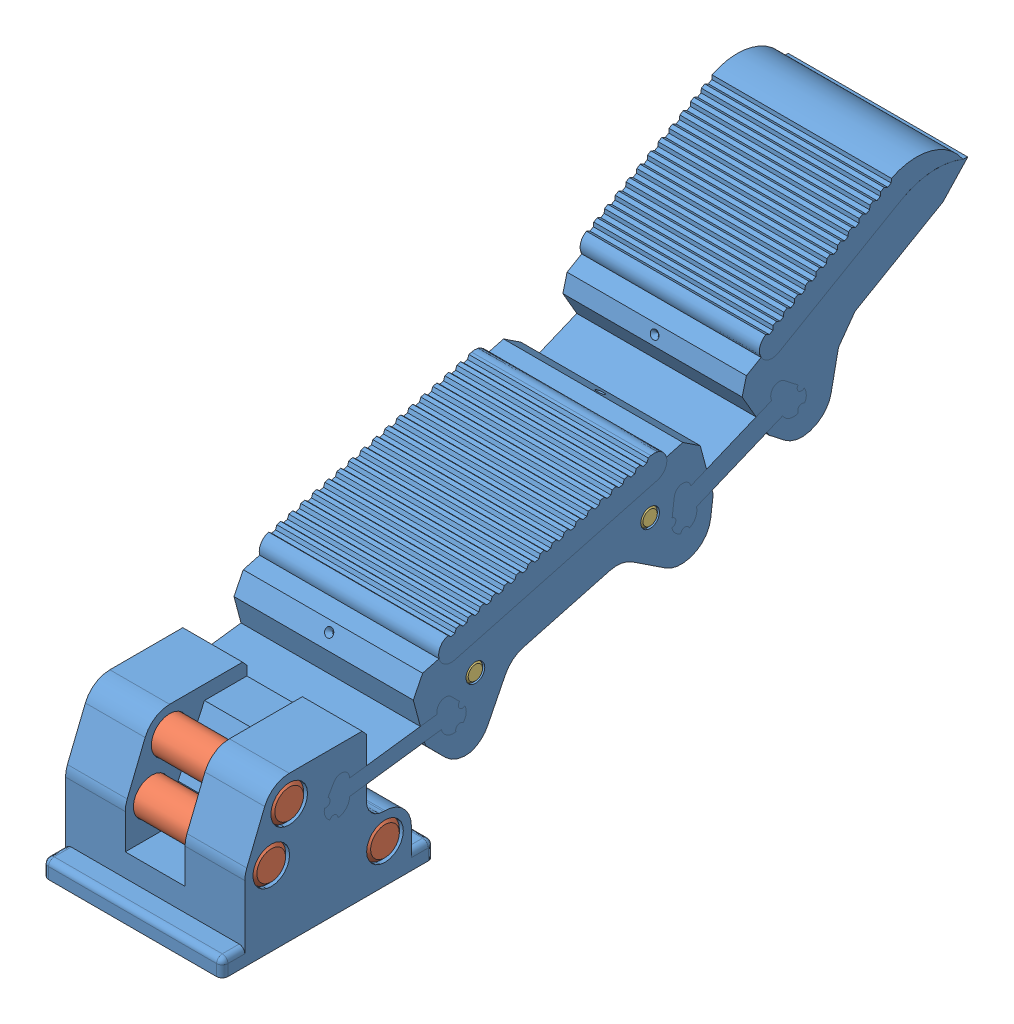
SolidWorks assembly block_finger_ff_t42, configuration Default. Lengths in mm.
Overall size (31.75 64.71 131.98).
8 component instances, 5 part files, 14 mates.
Components (placement in the parent):
- finger_ff_t42-1: finger_ff_t42 [Default] at origin size (31.75 64.71 131.98)
- 98381A544 D1-4 L5-4-1: 98381A544 D1-4 L5-4 [98381A544] at (0 1.7724 6.175) size (31.75 6.35 6.35)
- 98381A544 D1-4 L5-4-2: 98381A544 D1-4 L5-4 [98381A544] at (0 -6.0776 9.35) size (31.75 6.35 6.35)
- 98381A544 D1-4 L5-4-3: 98381A544 D1-4 L5-4 [98381A544] at (0 -12.4276 -10.7822) size (31.75 6.35 6.35)
- 98381A477 D1-8 L5-4-1: 98381A477 D1-8 L5-4 [98381A477] at (0 5.4025 -26.786) size (31.75 3.17 3.17)
- 98381A477 D1-8 L5-4-2: 98381A477 D1-8 L5-4 [98381A477] at (0 13.6905 -57.7172) size (31.75 3.17 3.17)
- 93365A120 4-40 insert-1: 93365A120 4-40 insert [93365A120] at (0 25.1633 -92.5321) x (0.85008 0.427177 -0.308032) z (-0.526653 0.689514 -0.497199) size (4.37 3.82 4.37)
- 91253A106 4-40 L1-4 countersunk-1: 91253A106 4-40 L1-4 countersunk [91253A106] at (0 23.9226 -94.2526) x (1 0 0) z (0 -0.584885 -0.811116) size (6.48 6.48 6.63)
Mates (geometry in assembly coordinates):
- Concentric1: concentric aligned: cylinder of finger_ff_t42-1 through (-15.875 1.7724 6.175) axis (1 0 0) radius 3.25; cylinder of 98381A544 D1-4 L5-4-1 through (-15.875 1.7724 6.175) axis (1 0 0) radius 3.175
- Coincident1: coincident aligned: plane of finger_ff_t42-1 through (15.875 -12.4276 -10.7822) normal (1 0 0); plane of 98381A544 D1-4 L5-4-1 through (15.875 1.7724 6.175) normal (1 0 0)
- Concentric2: concentric aligned: cylinder of finger_ff_t42-1 through (-15.875 -6.0776 9.35) axis (1 0 0) radius 3.25; cylinder of 98381A544 D1-4 L5-4-2 through (-15.875 -6.0776 9.35) axis (1 0 0) radius 3.175
- Coincident2: coincident aligned: plane of finger_ff_t42-1 through (15.875 -12.4276 -10.7822) normal (1 0 0); plane of 98381A544 D1-4 L5-4-2 through (15.875 -6.0776 9.35) normal (1 0 0)
- Concentric3: concentric aligned: cylinder of finger_ff_t42-1 through (-15.875 -12.4276 -10.7822) axis (1 0 0) radius 3.25; cylinder of 98381A544 D1-4 L5-4-3 through (-15.875 -12.4276 -10.7822) axis (1 0 0) radius 3.175
- Coincident3: coincident aligned: plane of finger_ff_t42-1 through (15.875 -12.4276 -10.7822) normal (1 0 0); plane of 98381A544 D1-4 L5-4-3 through (15.875 -12.4276 -10.7822) normal (1 0 0)
- Concentric4: concentric aligned: cylinder of finger_ff_t42-1 through (-15.875 5.4025 -26.786) axis (1 0 0) radius 1.6625; cylinder of 98381A477 D1-8 L5-4-1 through (-15.875 5.4025 -26.786) axis (1 0 0) radius 1.5875
- Coincident4: coincident aligned: plane of finger_ff_t42-1 through (15.875 -12.4276 -10.7822) normal (1 0 0); plane of 98381A477 D1-8 L5-4-1 through (15.875 5.4025 -26.786) normal (1 0 0)
- Concentric5: concentric aligned: cylinder of finger_ff_t42-1 through (-15.875 13.6905 -57.7172) axis (1 0 0) radius 1.6625; cylinder of 98381A477 D1-8 L5-4-2 through (-15.875 13.6905 -57.7172) axis (1 0 0) radius 1.5875
- Coincident5: coincident aligned: plane of finger_ff_t42-1 through (15.875 -12.4276 -10.7822) normal (1 0 0); plane of 98381A477 D1-8 L5-4-2 through (15.875 13.6905 -57.7172) normal (1 0 0)
- Concentric6: concentric aligned: cylinder of finger_ff_t42-1 through (0 27.7953 -88.8821) axis (0 -0.584885 -0.811116) radius 1.85; circle of 93365A120 4-40 insert-1
- Coincident6: coincident aligned: plane of finger_ff_t42-1 through (-20.875 27.1911 -93.9943) normal (0 -0.584885 -0.811116); plane of 93365A120 4-40 insert-1 through (0 25.1633 -92.5321) normal (0 -0.584885 -0.811116)
- Concentric7: concentric anti-aligned: circle of 93365A120 4-40 insert-1; circle of 91253A106 4-40 L1-4 countersunk-1
- Coincident7: coincident: circle of 93365A120 4-40 insert-1; cone of 91253A106 4-40 L1-4 countersunk-1 through (0 25.1557 -92.5426) axis (0 0.584885 0.811116)
